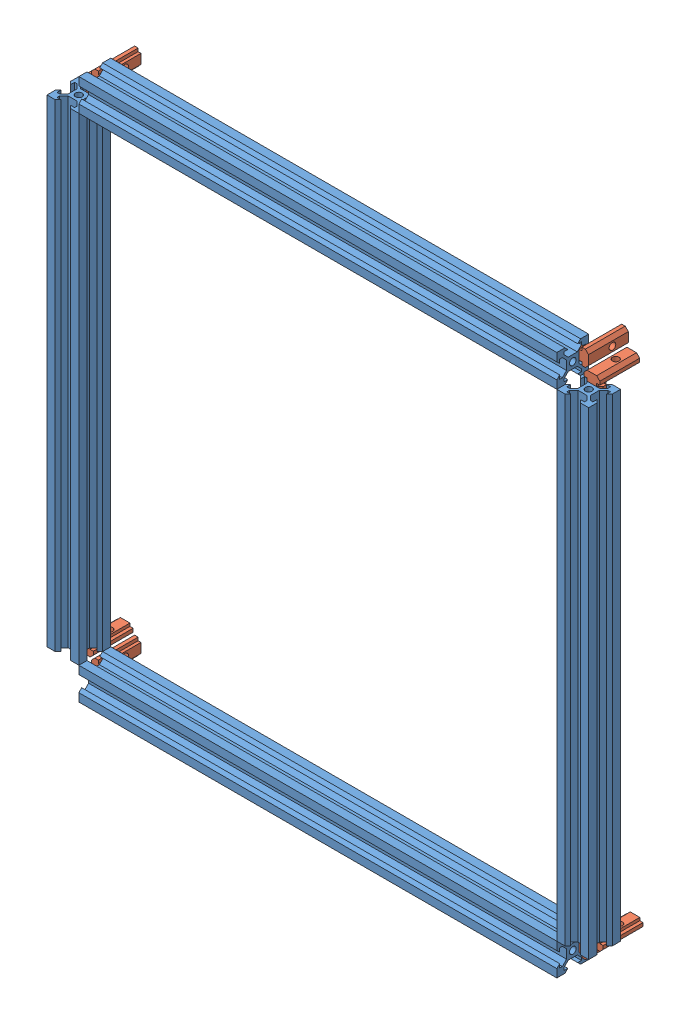
SolidWorks assembly layer30, configuration 默认. Lengths in mm.
Overall size (340 340 42.68).
12 component instances, 2 part files, 33 mates.
Components (placement in the parent):
- 2020lv_300-1: 2020lv_300 [默认] at (-45.5431 -220.7116 300) size (20 300 20)
- 2020lv_300-2: 2020lv_300 [默认] at (-55.5431 -230.7116 300) x (0 1 0) z (0 0 1) size (20 300 20)
- 2020lv_300-3: 2020lv_300 [默认] at (-55.5431 89.2884 300) x (0 1 0) z (0 0 1) size (20 300 20)
- 2020lv_300-4: 2020lv_300 [默认] at (-365.5431 -220.7116 300) size (20 300 20)
- 2020jiaocao-1: 2020jiaocao [默认] at (-47.4431 79.2884 293.1) x (0 0 -1) z (-1 0 0) size (25 26 10)
- 2020jiaocao-2: 2020jiaocao [默认] at (-55.5431 91.1884 293.1) x (0 0 -1) z (0 1 0) size (25 26 10)
- 2020jiaocao-3: 2020jiaocao [默认] at (-355.5431 89.3884 293) x (0 0 -1) z (0 -1 0) size (25 26 10)
- 2020jiaocao-4: 2020jiaocao [默认] at (-365.6431 79.2884 289.3206) x (0 0 -1) z (-1 0 0) size (25 26 10)
- 2020jiaocao-5: 2020jiaocao [默认] at (-365.4431 -220.7116 293) x (0 0 -1) z (1 0 0) size (25 26 10)
- 2020jiaocao-6: 2020jiaocao [默认] at (-355.5431 -230.8116 293) x (0 0 -1) z (0 -1 0) size (25 26 10)
- 2020jiaocao-7: 2020jiaocao [默认] at (-55.5431 -230.8116 293) x (0 0 -1) z (0 1 0) size (25 26 10)
- 2020jiaocao-8: 2020jiaocao [默认] at (-45.4431 -220.7116 293) x (0 0 -1) z (1 0 0) size (25 26 10)
Mates (geometry in assembly coordinates):
- 重合2: coincident aligned: plane of 2020lv_300-1 through (-35.5431 79.2884 310) normal (0 0 1); plane of 2020lv_300-4 through (-355.5431 79.2884 310) normal (0 0 1)
- 重合3: coincident aligned: plane of 2020lv_300-1 through (-45.5431 -220.7116 300) normal (0 -1 0); plane of 2020lv_300-4 through (-365.5431 -220.7116 300) normal (0 -1 0)
- 重合4: coincident aligned: plane of 2020lv_300-2 through (-355.5431 -240.7116 310) normal (0 0 1); plane of 2020lv_300-4 through (-355.5431 79.2884 310) normal (0 0 1)
- 重合6: coincident anti-aligned: plane of 2020lv_300-2 through (-355.5431 -220.7116 310) normal (0 1 0); plane of 2020lv_300-4 through (-365.5431 -220.7116 300) normal (0 -1 0)
- 重合7: coincident anti-aligned: plane of 2020lv_300-2 through (-355.5431 -230.7116 300) normal (-1 0 0); plane of 2020lv_300-4 through (-355.5431 79.2884 310) normal (1 0 0)
- 重合8: coincident anti-aligned: plane of 2020lv_300-1 through (-55.5431 79.2884 290) normal (-1 0 0); plane of 2020lv_300-2 through (-55.5431 -230.7116 300) normal (1 0 0)
- 重合9: coincident aligned: plane of 2020lv_300-1 through (-35.5431 79.2884 310) normal (0 0 1); plane of 2020lv_300-3 through (-355.5431 99.2884 310) normal (0 0 1)
- 重合10: coincident anti-aligned: plane of 2020lv_300-1 through (-55.5431 79.2884 310) normal (-1 0 0); plane of 2020lv_300-3 through (-55.5431 89.2884 300) normal (1 0 0)
- 重合11: coincident anti-aligned: plane of 2020lv_300-3 through (-355.5431 79.2884 310) normal (0 -1 0); plane of 2020lv_300-4 through (-365.5431 79.2884 300) normal (0 1 0)
- 重合12: coincident anti-aligned: plane of 2020lv_300-1 through (-48.3824 79.2884 296.1) normal (0 0 -1); plane of 2020jiaocao-1 through (-44.4431 59.2884 296.1) normal (0 0 1)
- 重合13: coincident anti-aligned: plane of 2020lv_300-1 through (-45.5431 79.2884 300) normal (0 1 0); plane of 2020jiaocao-1 through (-50.4431 79.2884 271.1) normal (0 -1 0)
- 重合14: coincident: line of 2020lv_300-1 through (-42.4431 79.2884 291.8) axis (0 -1 0); plane of 2020jiaocao-1 through (-42.4431 59.2884 294.1) normal (1 0 0)
- 重合17: coincident anti-aligned: plane of 2020lv_300-3 through (-355.5431 86.449 296.1) normal (0 0 -1); plane of 2020jiaocao-2 through (-75.5431 88.1884 296.1) normal (0 0 1)
- 重合18: coincident: line of 2020lv_300-3 through (-355.5431 86.1884 291.8) axis (1 0 0); plane of 2020jiaocao-2 through (-75.5431 86.1884 294.1) normal (0 -1 0)
- 重合19: coincident anti-aligned: plane of 2020lv_300-3 through (-55.5431 89.2884 300) normal (1 0 0); plane of 2020jiaocao-2 through (-55.5431 94.1884 271.1) normal (-1 0 0)
- 重合20: coincident aligned: plane of 2020lv_300-3 through (-355.5431 99.2884 290) normal (0 0 -1); plane of 2020jiaocao-3 through (-335.5431 86.3884 290) normal (0 0 -1)
- 重合22: coincident anti-aligned: plane of 2020lv_300-3 through (-355.5431 89.2884 300) normal (-1 0 0); plane of 2020jiaocao-3 through (-355.5431 86.3884 271) normal (1 0 0)
- 重合23: coincident: line of 2020lv_300-3 through (-355.5431 92.3884 291.8) axis (1 0 0); plane of 2020jiaocao-3 through (-335.5431 92.3884 291.8) normal (0 1 0)
- 重合24: coincident anti-aligned: plane of 2020lv_300-4 through (-365.5431 79.2884 300) normal (0 1 0); plane of 2020jiaocao-4 through (-368.6431 79.2884 267.3206) normal (0 -1 0)
- 重合25: coincident: line of 2020lv_300-4 through (-368.6431 79.2884 291.8) axis (0 -1 0); plane of 2020jiaocao-4 through (-368.6431 59.2884 288.1206) normal (-1 0 0)
- 平行1: parallel aligned: plane of 2020lv_300-4 through (-369.4431 79.2884 297.1607) normal (-1 0 0); plane of 2020jiaocao-4 through (-370.6431 83.2884 267.3206) normal (-1 0 0)
- 重合27: coincident aligned: plane of 2020lv_300-4 through (-375.5431 79.2884 290) normal (0 0 -1); plane of 2020jiaocao-5 through (-362.4431 -200.7116 290) normal (0 0 -1)
- 重合28: coincident anti-aligned: plane of 2020lv_300-4 through (-365.5431 -220.7116 300) normal (0 -1 0); plane of 2020jiaocao-5 through (-362.4431 -220.7116 271) normal (0 1 0)
- 重合29: coincident: line of 2020lv_300-4 through (-362.4431 79.2884 291.8) axis (0 -1 0); plane of 2020jiaocao-5 through (-362.4431 -200.7116 291.8) normal (1 0 0)
- 重合30: coincident anti-aligned: plane of 2020lv_300-2 through (-355.5431 -230.7116 300) normal (-1 0 0); plane of 2020jiaocao-6 through (-355.5431 -233.8116 271) normal (1 0 0)
- 重合31: coincident aligned: plane of 2020lv_300-2 through (-355.5431 -240.7116 290) normal (0 0 -1); plane of 2020jiaocao-6 through (-335.5431 -233.8116 290) normal (0 0 -1)
- 重合32: coincident: line of 2020lv_300-2 through (-355.5431 -233.8116 291.8) axis (1 0 0); plane of 2020jiaocao-6 through (-335.5431 -233.8116 291.8) normal (0 -1 0)
- 重合33: coincident aligned: plane of 2020lv_300-2 through (-355.5431 -240.7116 290) normal (0 0 -1); plane of 2020jiaocao-7 through (-75.5431 -227.8116 290) normal (0 0 -1)
- 重合34: coincident anti-aligned: plane of 2020lv_300-2 through (-55.5431 -230.7116 300) normal (1 0 0); plane of 2020jiaocao-7 through (-55.5431 -227.8116 271) normal (-1 0 0)
- 重合35: coincident: line of 2020lv_300-2 through (-355.5431 -233.8116 291.8) axis (1 0 0); plane of 2020jiaocao-7 through (-75.5431 -233.8116 291.8) normal (0 -1 0)
- 重合36: coincident anti-aligned: plane of 2020lv_300-1 through (-45.5431 -220.7116 300) normal (0 -1 0); plane of 2020jiaocao-8 through (-42.4431 -220.7116 271) normal (0 1 0)
- 重合37: coincident aligned: plane of 2020lv_300-1 through (-35.5431 79.2884 290) normal (0 0 -1); plane of 2020jiaocao-8 through (-42.4431 -200.7116 290) normal (0 0 -1)
- 重合38: coincident: line of 2020lv_300-1 through (-42.4431 79.2884 291.8) axis (0 -1 0); plane of 2020jiaocao-8 through (-42.4431 -200.7116 291.8) normal (1 0 0)
